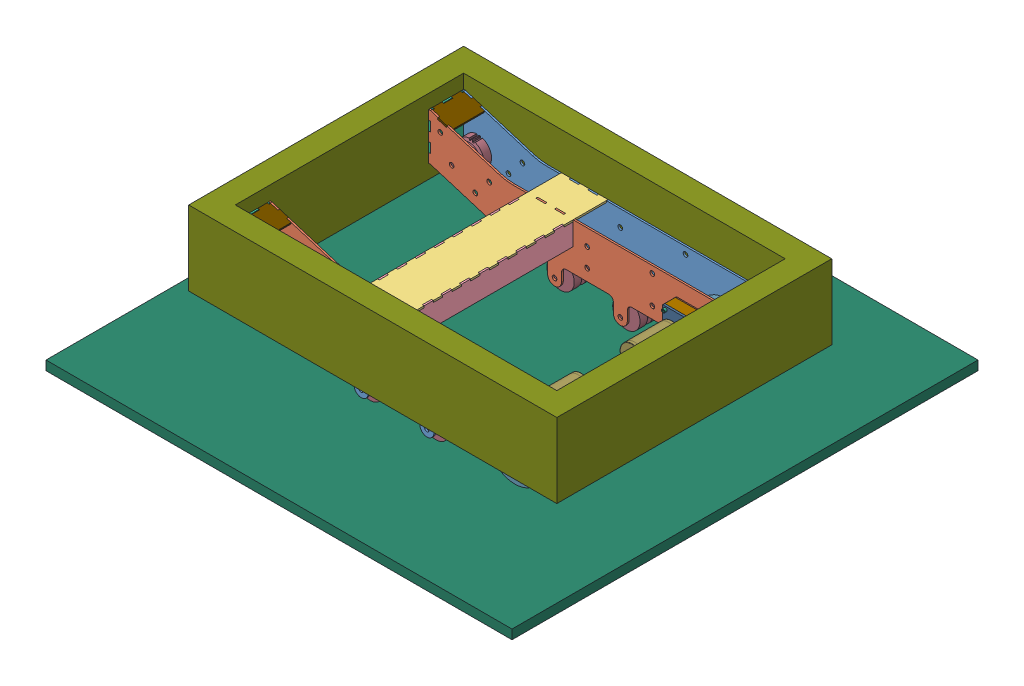
SolidWorks assembly base v2, configuration Default. Lengths in mm.
Overall size (1270 330.2 1270).
109 component instances, 36 part files, 86 mates.
Components (placement in the parent):
- outer wall-1: outer wall [Default] at origin size (876.3 248.48 4.83)
- inner wall-1: inner wall [Default] at (-656.7743 299.8998 -90.424) size (871.47 248.48 4.83)
- inner wall-2: inner wall [Default] at (-656.7743 299.8998 -527.05) size (871.47 248.48 4.83)
- outer wall-2: outer wall [Default] at (0 0 -617.474) size (876.3 248.48 4.83)
- center top support-1: center top support [Default] at (-609.6 198.374 -617.474) x (0 0 1) z (-1 0 0) size (622.3 4.83 127)
- center side support-1: center side support [Default] at (-487.426 139.7 4.826) x (0 0 -1) z (1 0 0) size (441.45 63.5 4.83)
- center side support-2: center side support [Default] at (-604.774 139.7 -617.474) x (0 0 1) z (-1 0 0) size (441.45 63.5 4.83)
- back wall-1: back wall [Default] at (-9.652 76.2 4.826) x (0 0 -1) z (1 0 0) size (441.45 127 4.83)
- front plate-1: front plate [Default] at (-871.474 139.7 -90.424) x (0 0 1) z (-1 0 0) size (95.25 127 4.83)
- front plate-2: front plate [Default] at (-871.474 139.7 -617.474) x (0 0 1) z (-1 0 0) size (95.25 127 4.83)
- back plate left-1: back plate left [Default] at (-4.826 76.2 4.826) x (0 0 -1) z (1 0 0) size (315.98 127 4.83)
- back plate right-1: back plate right [Default] at (-4.826 76.2 4.826) x (0 0 -1) z (1 0 0) size (311.15 127 4.83)
- am-0145+Updated+Toughbox+2015-1: am-0145+Updated+Toughbox+2015 [Default] at (-172.8426 75.0742 -202.6767) size (127.03 127 97.81)
  - am-2650 TB Spacer-1: am-2650 TB Spacer [Default] at (-20.7449 79.3887 80.3249) size (127 14.35 28.75)
  - am-0155 Toughbox Motor Plate-1: am-0155 Toughbox Motor Plate [Default] at (21.1445 38.6364 74.7369) x (1 0 0) z (0 1 0) size (127 5.59 127)
  - am-2650 TB Spacer-2: am-2650 TB Spacer [Default] at (90.4055 -31.7363 80.3249) x (-1 0 0) z (0 0 1) size (127 14.35 28.75)
  - Toughbox d02 am-0261-1: Toughbox d02 am-0261 [Default] at (21.1699 38.6364 109.0777) x (1 0 0) z (0 1 0) size (127 3.17 127)
  - FR6ZZ Bearing-1: FR6ZZ Bearing [Default] at (40.6889 12.4563 81.8489) x (0.923728 0.383049 0) z (0 0 -1) size (24.69 24.69 7.16)
  - FR6ZZ Bearing-2: FR6ZZ Bearing [Default] at (40.6889 53.1471 81.8489) x (0.923728 0.383049 0) z (0 0 -1) size (24.69 24.69 7.16)
  - 10-32x0500_shcs_HX-SHCS 0.19-32x1.375x1-C-1: 10-32x0500_shcs_HX-SHCS 0.19-32x1.375x1-C [Default] at (-3.3906 4.7762 85.1509) x (0 0 -1) z (1 0 0) size (17.53 7.94 7.94)
  - 10-32x0500_shcs_HX-SHCS 0.19-32x1.375x1-C-2: 10-32x0500_shcs_HX-SHCS 0.19-32x1.375x1-C [Default] at (-3.3906 55.5762 85.1509) x (0 0 -1) z (1 0 0) size (17.53 7.94 7.94)
  - 10-32x0500_shcs_HX-SHCS 0.19-32x1.375x1-C-3: 10-32x0500_shcs_HX-SHCS 0.19-32x1.375x1-C [Default] at (73.0258 55.5762 85.1509) x (0 0 -1) z (1 0 0) size (17.53 7.94 7.94)
  - 10-32x0500_shcs_HX-SHCS 0.19-32x1.375x1-C-4: 10-32x0500_shcs_HX-SHCS 0.19-32x1.375x1-C [Default] at (73.0258 4.7762 85.1509) x (0 0 -1) z (1 0 0) size (17.53 7.94 7.94)
  - 5-16 washer-1: 5-16 washer [Default] at (-3.3906 30.1762 78.8009) size (17.53 17.53 1.47)
  - 5-16 washer-2: 5-16 washer [Default] at (-3.3906 30.1762 80.2741) size (17.53 17.53 1.47)
  - 5-16 washer-3: 5-16 washer [Default] at (73.0258 30.1762 78.8009) size (17.53 17.53 1.47)
  - 5-16 washer-4: 5-16 washer [Default] at (73.0258 30.1762 80.2741) size (17.53 17.53 1.47)
  - Toughbox Small Hex Shaft-1: Toughbox Small Hex Shaft [Default] at (34.8176 44.1716 75.8037) x (0.5 -0.866025 0) z (0 0 1) size (11 9.53 38.11)
  - TB Output Shaft-1: TB Output Shaft [Default] at (-2.2613 22.7278 107.2489) x (-0.997664 0.068316 0) z (0.068316 0.997664 0) size (14.66 92.33 12.7)
  - FR6ZZ Bearing-3: FR6ZZ Bearing [Default] at (43.7045 38.1296 107.5537) size (24.69 24.69 7.16)
  - FR8ZZ Bearing-1: FR8ZZ Bearing [Default] at (43.7045 -2.5612 107.5029) size (31.75 31.75 7.95)
  - 14T CIM Gear-1: 14T CIM Gear [Default] at (-3.3906 30.1762 81.7473) size (20.03 20.32 12.7)
  - 14T CIM Gear-2: 14T CIM Gear [Default] at (73.0258 30.1762 81.7473) x (0.98536 0.170489 0) z (0 0 1) size (20.03 20.32 12.7)
  - 8mm_spring_clip am-0033-1: 8mm_spring_clip am-0033 [Default] at (-3.3906 30.1762 94.4473) x (0 0 1) z (-1 0 0) size (1.12 14.83 14.83)
  - 8mm_spring_clip am-0033-2: 8mm_spring_clip am-0033 [Default] at (73.0258 30.1762 94.4473) x (0 0 1) z (-1 0 0) size (1.12 14.83 14.83)
  - 500-e-klip_smart-1: 500-e-klip_smart [Default] at (62.138 11.0174 96.4031) x (1 0 0) z (0 1 0) size (19.07 1.27 20.95)
  - 50T 20dp 375hex_Inch - Spur gear 20DP 50T 14.5PA .372FW ---S50N3.0H2.0L0.25N-1: 50T 20dp 375hex_Inch - Spur gear 20DP 50T 14.5PA .372FW ---S50N3.0H2.0L0.25N [Default] at (34.8176 44.1716 92.0089) x (0 0 -1) z (1 0 0) size (10.16 65.97 66.04)
  - 14T 20dp 375hex_Inch - Spur gear 20DP 14T 14.5PA .568FW ---S14N3.0H2.0L0.25N-1: 14T 20dp 375hex_Inch - Spur gear 20DP 14T 14.5PA .568FW ---S14N3.0H2.0L0.25N [Default] at (34.843 44.1716 92.0089) x (0 0 1) z (-1 0 0) size (15.14 19.97 20.32)
  - 50T 20dp 500hex-1: 50T 20dp 500hex [Default] at (34.8176 3.4808 96.4031) x (0.997664 -0.068316 0) z (0 0 1) size (65.97 66.04 10.62)
  - SHCS 14-20 x 2-1: SHCS 14-20 x 2 [Default] at (90.3801 79.3887 68.1837) x (1 0 0) z (0 1 0) size (9.53 57.35 9.53)
  - SHCS 14-20 x 2-2: SHCS 14-20 x 2 [Default] at (-20.7449 79.3887 68.1837) x (1 0 0) z (0 1 0) size (9.53 57.35 9.53)
  - SHCS 14-20 x 2-3: SHCS 14-20 x 2 [Default] at (-20.7449 -31.7363 68.1837) x (1 0 0) z (0 1 0) size (9.53 57.35 9.53)
  - SHCS 14-20 x 2-4: SHCS 14-20 x 2 [Default] at (90.3801 -31.7363 68.1837) x (1 0 0) z (0 1 0) size (9.53 57.35 9.53)
  - 14-20 Nylock Nut_97135A210-1: 14-20 Nylock Nut_97135A210 [Default] at (-20.7195 79.3887 112.2527) x (1 0 0) z (0 -1 0) size (11.11 8.13 12.83)
  - 14-20 Nylock Nut_97135A210-2: 14-20 Nylock Nut_97135A210 [Default] at (-20.7195 -31.7363 112.2527) x (1 0 0) z (0 -1 0) size (11.11 8.13 12.83)
  - 14-20 Nylock Nut_97135A210-3: 14-20 Nylock Nut_97135A210 [Default] at (90.4055 -31.7363 112.2527) x (1 0 0) z (0 -1 0) size (11.11 8.13 12.83)
  - 14-20 Nylock Nut_97135A210-4: 14-20 Nylock Nut_97135A210 [Default] at (90.4055 79.3887 112.2527) x (1 0 0) z (0 -1 0) size (11.11 8.13 12.83)
  - 0.25 Flat Washer_Preferred Wide FW 0.25-1: 0.25 Flat Washer_Preferred Wide FW 0.25 [Default] at (34.8176 3.4808 154.3659) x (0 0 -1) z (1 0 0) size (1.4 15.88 15.88)
  - BHCS 14-20 x 0.5-1: BHCS 14-20 x 0.5 [Default] at (34.8176 3.4808 159.8269) x (0.554675 -0.832067 0) z (-0.832067 -0.554675 0) size (11.69 16.79 11.69)
  - 2mm x 2mm x 10mm Machine Key_smart-1: 2mm x 2mm x 10mm Machine Key_smart [Default] at (-25.2074 30.9762 84.4473) x (0 0 1) z (0 -1 0) size (10 2 2)
  - 2mm x 2mm x 10mm Machine Key_smart-2: 2mm x 2mm x 10mm Machine Key_smart [Default] at (79.0195 13.1317 84.4473) x (0 0 1) z (0.98536 0.170489 0) size (10 2 2)
  - 125 x 124 x 700 Machine Key-1: 125 x 124 x 700 Machine Key [Default] at (33.4941 11.4893 125.5831) x (0 0 1) z (-0.997664 0.068316 0) size (17.78 3.17 3.17)
- am-0145+Updated+Toughbox+2015-2: am-0145+Updated+Toughbox+2015 [Default] at (-103.2074 75.0742 -409.9713) x (-1 0 0) z (0 0 -1) size (127.03 127 97.81)
  - am-2650 TB Spacer-1: am-2650 TB Spacer [Default] at (-20.7449 79.3887 80.3249) size (127 14.35 28.75)
  - am-0155 Toughbox Motor Plate-1: am-0155 Toughbox Motor Plate [Default] at (21.1445 38.6364 74.7369) x (1 0 0) z (0 1 0) size (127 5.59 127)
  - am-2650 TB Spacer-2: am-2650 TB Spacer [Default] at (90.4055 -31.7363 80.3249) x (-1 0 0) z (0 0 1) size (127 14.35 28.75)
  - Toughbox d02 am-0261-1: Toughbox d02 am-0261 [Default] at (21.1699 38.6364 109.0777) x (1 0 0) z (0 1 0) size (127 3.17 127)
  - FR6ZZ Bearing-1: FR6ZZ Bearing [Default] at (40.6889 12.4563 81.8489) x (0.923728 0.383049 0) z (0 0 -1) size (24.69 24.69 7.16)
  - FR6ZZ Bearing-2: FR6ZZ Bearing [Default] at (40.6889 53.1471 81.8489) x (0.923728 0.383049 0) z (0 0 -1) size (24.69 24.69 7.16)
  - 10-32x0500_shcs_HX-SHCS 0.19-32x1.375x1-C-1: 10-32x0500_shcs_HX-SHCS 0.19-32x1.375x1-C [Default] at (-3.3906 4.7762 85.1509) x (0 0 -1) z (1 0 0) size (17.53 7.94 7.94)
  - 10-32x0500_shcs_HX-SHCS 0.19-32x1.375x1-C-2: 10-32x0500_shcs_HX-SHCS 0.19-32x1.375x1-C [Default] at (-3.3906 55.5762 85.1509) x (0 0 -1) z (1 0 0) size (17.53 7.94 7.94)
  - 10-32x0500_shcs_HX-SHCS 0.19-32x1.375x1-C-3: 10-32x0500_shcs_HX-SHCS 0.19-32x1.375x1-C [Default] at (73.0258 55.5762 85.1509) x (0 0 -1) z (1 0 0) size (17.53 7.94 7.94)
  - 10-32x0500_shcs_HX-SHCS 0.19-32x1.375x1-C-4: 10-32x0500_shcs_HX-SHCS 0.19-32x1.375x1-C [Default] at (73.0258 4.7762 85.1509) x (0 0 -1) z (1 0 0) size (17.53 7.94 7.94)
  - 5-16 washer-1: 5-16 washer [Default] at (-3.3906 30.1762 78.8009) size (17.53 17.53 1.47)
  - 5-16 washer-2: 5-16 washer [Default] at (-3.3906 30.1762 80.2741) size (17.53 17.53 1.47)
  - 5-16 washer-3: 5-16 washer [Default] at (73.0258 30.1762 78.8009) size (17.53 17.53 1.47)
  - 5-16 washer-4: 5-16 washer [Default] at (73.0258 30.1762 80.2741) size (17.53 17.53 1.47)
  - Toughbox Small Hex Shaft-1: Toughbox Small Hex Shaft [Default] at (34.8176 44.1716 75.8037) x (0.5 -0.866025 0) z (0 0 1) size (11 9.53 38.11)
  - TB Output Shaft-1: TB Output Shaft [Default] at (-2.2613 22.7278 107.2489) x (-0.997664 0.068316 0) z (0.068316 0.997664 0) size (14.66 92.33 12.7)
  - FR6ZZ Bearing-3: FR6ZZ Bearing [Default] at (43.7045 38.1296 107.5537) size (24.69 24.69 7.16)
  - FR8ZZ Bearing-1: FR8ZZ Bearing [Default] at (43.7045 -2.5612 107.5029) size (31.75 31.75 7.95)
  - 14T CIM Gear-1: 14T CIM Gear [Default] at (-3.3906 30.1762 81.7473) size (20.03 20.32 12.7)
  - 14T CIM Gear-2: 14T CIM Gear [Default] at (73.0258 30.1762 81.7473) x (0.98536 0.170489 0) z (0 0 1) size (20.03 20.32 12.7)
  - 8mm_spring_clip am-0033-1: 8mm_spring_clip am-0033 [Default] at (-3.3906 30.1762 94.4473) x (0 0 1) z (-1 0 0) size (1.12 14.83 14.83)
  - 8mm_spring_clip am-0033-2: 8mm_spring_clip am-0033 [Default] at (73.0258 30.1762 94.4473) x (0 0 1) z (-1 0 0) size (1.12 14.83 14.83)
  - 500-e-klip_smart-1: 500-e-klip_smart [Default] at (62.138 11.0174 96.4031) x (1 0 0) z (0 1 0) size (19.07 1.27 20.95)
  - 50T 20dp 375hex_Inch - Spur gear 20DP 50T 14.5PA .372FW ---S50N3.0H2.0L0.25N-1: 50T 20dp 375hex_Inch - Spur gear 20DP 50T 14.5PA .372FW ---S50N3.0H2.0L0.25N [Default] at (34.8176 44.1716 92.0089) x (0 0 -1) z (1 0 0) size (10.16 65.97 66.04)
  - 14T 20dp 375hex_Inch - Spur gear 20DP 14T 14.5PA .568FW ---S14N3.0H2.0L0.25N-1: 14T 20dp 375hex_Inch - Spur gear 20DP 14T 14.5PA .568FW ---S14N3.0H2.0L0.25N [Default] at (34.843 44.1716 92.0089) x (0 0 1) z (-1 0 0) size (15.14 19.97 20.32)
  - 50T 20dp 500hex-1: 50T 20dp 500hex [Default] at (34.8176 3.4808 96.4031) x (0.997664 -0.068316 0) z (0 0 1) size (65.97 66.04 10.62)
  - SHCS 14-20 x 2-1: SHCS 14-20 x 2 [Default] at (90.3801 79.3887 68.1837) x (1 0 0) z (0 1 0) size (9.53 57.35 9.53)
  - SHCS 14-20 x 2-2: SHCS 14-20 x 2 [Default] at (-20.7449 79.3887 68.1837) x (1 0 0) z (0 1 0) size (9.53 57.35 9.53)
  - SHCS 14-20 x 2-3: SHCS 14-20 x 2 [Default] at (-20.7449 -31.7363 68.1837) x (1 0 0) z (0 1 0) size (9.53 57.35 9.53)
  - SHCS 14-20 x 2-4: SHCS 14-20 x 2 [Default] at (90.3801 -31.7363 68.1837) x (1 0 0) z (0 1 0) size (9.53 57.35 9.53)
  - 14-20 Nylock Nut_97135A210-1: 14-20 Nylock Nut_97135A210 [Default] at (-20.7195 79.3887 112.2527) x (1 0 0) z (0 -1 0) size (11.11 8.13 12.83)
  - 14-20 Nylock Nut_97135A210-2: 14-20 Nylock Nut_97135A210 [Default] at (-20.7195 -31.7363 112.2527) x (1 0 0) z (0 -1 0) size (11.11 8.13 12.83)
  - 14-20 Nylock Nut_97135A210-3: 14-20 Nylock Nut_97135A210 [Default] at (90.4055 -31.7363 112.2527) x (1 0 0) z (0 -1 0) size (11.11 8.13 12.83)
  - 14-20 Nylock Nut_97135A210-4: 14-20 Nylock Nut_97135A210 [Default] at (90.4055 79.3887 112.2527) x (1 0 0) z (0 -1 0) size (11.11 8.13 12.83)
  - 0.25 Flat Washer_Preferred Wide FW 0.25-1: 0.25 Flat Washer_Preferred Wide FW 0.25 [Default] at (34.8176 3.4808 154.3659) x (0 0 -1) z (1 0 0) size (1.4 15.88 15.88)
  - BHCS 14-20 x 0.5-1: BHCS 14-20 x 0.5 [Default] at (34.8176 3.4808 159.8269) x (0.554675 -0.832067 0) z (-0.832067 -0.554675 0) size (11.69 16.79 11.69)
  - 2mm x 2mm x 10mm Machine Key_smart-1: 2mm x 2mm x 10mm Machine Key_smart [Default] at (-25.2074 30.9762 84.4473) x (0 0 1) z (0 -1 0) size (10 2 2)
  - 2mm x 2mm x 10mm Machine Key_smart-2: 2mm x 2mm x 10mm Machine Key_smart [Default] at (79.0195 13.1317 84.4473) x (0 0 1) z (0.98536 0.170489 0) size (10 2 2)
  - 125 x 124 x 700 Machine Key-1: 125 x 124 x 700 Machine Key [Default] at (33.4941 11.4893 125.5831) x (0 0 1) z (-0.997664 0.068316 0) size (17.78 3.17 3.17)
- CIM 217-2000-1: CIM 217-2000 [Default] at (-176.2332 105.2504 -484.7082) x (0 0 1) z (-1 0 0) size (150.2 64.01 64.01)
- CIM 217-2000-2: CIM 217-2000 [Default] at (-99.8168 105.2504 -484.7082) x (0 0 1) z (-1 0 0) size (150.2 64.01 64.01)
- CIM 217-2000-3: CIM 217-2000 [Default] at (-176.2332 105.2504 -127.9398) x (0 0 -1) z (1 0 0) size (150.2 64.01 64.01)
- CIM 217-2000-4: CIM 217-2000 [Default] at (-99.8168 105.2504 -127.9398) x (0 0 -1) z (1 0 0) size (150.2 64.01 64.01)
- al55tk10k13_24-0_nohub_d-12h7-1: al55tk10k13_24-0_nohub_d-12h7 [Default] at (-353.925 37.275 -46.55) size (74.55 74.36 55)
- al55tk10k13_48-0_nohub_d-16h7-1: al55tk10k13_48-0_nohub_d-16h7 [Default] at (-138.025 78.555 -46.55) size (150.95 150.86 55)
- al55tk10k13_24-0_nohub_d-12h7-2: al55tk10k13_24-0_nohub_d-12h7 [Default] at (-353.925 37.275 -566.098) size (74.55 74.36 55)
- al55tk10k13_48-0_nohub_d-16h7-2: al55tk10k13_48-0_nohub_d-16h7 [Default] at (-138.025 78.555 -566.098) size (150.95 150.86 55)
- al55tk10k13_24-0_nohub_d-12h7-3: al55tk10k13_24-0_nohub_d-12h7 [Default] at (-533.215 40.455 -46.55) size (74.55 74.36 55)
- al55tk10k13_24-0_nohub_d-12h7-4: al55tk10k13_24-0_nohub_d-12h7 [Default] at (-813.625 166.175 -46.55) size (74.55 74.36 55)
- al55tk10k13_24-0_nohub_d-12h7-5: al55tk10k13_24-0_nohub_d-12h7 [Default] at (-813.625 166.175 -566.098) size (74.55 74.36 55)
- al55tk10k13_24-0_nohub_d-12h7-6: al55tk10k13_24-0_nohub_d-12h7 [Default] at (-533.215 40.455 -566.098) size (74.55 74.36 55)
- ground-1: ground [Default] at (-1073.15 0 323.85) size (1270 25.4 1270)
- bumper zone-1: bumper zone [Default] at (0 0 4.826) size (1003.3 203.2 749.3)
- back top plate-1: back top plate [Default] at (-4.826 198.374 4.826) x (0 0 -1) z (1 0 0) size (441.45 4.83 63.5)
- front top plate-1: front top plate [Default] at (-876.3 263.137 -522.224) x (0.955668 -0.294445 0) z (0 0 1) size (63.5 4.83 95.25)
- front top plate-2: front top plate [Default] at (-876.3 263.137 4.826) x (0.955668 -0.294445 0) z (0 0 1) size (63.5 4.83 95.25)
Mates (geometry in assembly coordinates):
- Coincident6: coincident aligned: plane of outer wall-1 through (-95.4774 63.5 4.826) normal (0 0 1); plane of center top support-1 through (-609.6 203.2 4.826) normal (0 0 1)
- Coincident7: coincident anti-aligned: plane of outer wall-1 through (-482.6 0 0) normal (-1 0 0); plane of center top support-1 through (-482.6 203.2 -617.474) normal (1 0 0)
- Coincident8: coincident aligned: plane of outer wall-1 through (-665.3748 203.2 4.826) normal (0 1 0); plane of center top support-1 through (-609.6 203.2 -617.474) normal (0 1 0)
- Coincident10: coincident aligned: plane of inner wall-1 through (0 203.2 -85.598) normal (0 1 0); plane of center top support-1 through (-609.6 203.2 -617.474) normal (0 1 0)
- Coincident11: coincident anti-aligned: plane of inner wall-1 through (-646.2537 203.2 -90.424) normal (0 0 -1); plane of center top support-1 through (-609.6 203.2 -90.424) normal (0 0 1)
- Coincident12: coincident anti-aligned: plane of inner wall-1 through (-482.6 203.2 -85.598) normal (-1 0 0); plane of center top support-1 through (-482.6 203.2 -617.474) normal (1 0 0)
- Coincident13: coincident anti-aligned: plane of inner wall-2 through (-482.6 203.2 -522.224) normal (-1 0 0); plane of center top support-1 through (-482.6 203.2 -617.474) normal (1 0 0)
- Coincident14: coincident aligned: plane of inner wall-2 through (0 203.2 -522.224) normal (0 1 0); plane of center top support-1 through (-609.6 203.2 -617.474) normal (0 1 0)
- Coincident15: coincident anti-aligned: plane of inner wall-2 through (-646.2537 203.2 -522.224) normal (0 0 1); plane of center top support-1 through (-609.6 203.2 -522.224) normal (0 0 -1)
- Coincident16: coincident aligned: plane of outer wall-2 through (-95.4774 63.5 -617.474) normal (0 0 -1); plane of center top support-1 through (-609.6 203.2 -617.474) normal (0 0 -1)
- Coincident17: coincident aligned: plane of outer wall-2 through (-665.3748 203.2 -612.648) normal (0 1 0); plane of center top support-1 through (-609.6 203.2 -617.474) normal (0 1 0)
- Coincident18: coincident anti-aligned: plane of outer wall-2 through (-609.6 0 -617.474) normal (1 0 0); plane of center top support-1 through (-609.6 203.2 -617.474) normal (-1 0 0)
- Coincident19: coincident aligned: plane of center top support-1 through (-482.6 203.2 -617.474) normal (1 0 0); plane of center side support-1 through (-482.6 139.7 4.826) normal (1 0 0)
- Coincident20: coincident aligned: plane of center top support-1 through (-609.6 203.2 -617.474) normal (0 1 0); plane of center side support-1 through (-482.6 203.2 -115.824) normal (0 1 0)
- Coincident21: coincident aligned: plane of inner wall-1 through (-646.2537 203.2 -85.598) normal (0 0 1); plane of center side support-1 through (-482.6 177.8 -85.598) normal (0 0 1)
- Coincident22: coincident aligned: plane of center top support-1 through (-609.6 203.2 -617.474) normal (-1 0 0); plane of center side support-2 through (-609.6 139.7 -617.474) normal (-1 0 0)
- Coincident23: coincident aligned: plane of center top support-1 through (-609.6 203.2 -617.474) normal (0 1 0); plane of center side support-2 through (-609.6 203.2 -496.824) normal (0 1 0)
- Coincident24: coincident aligned: plane of inner wall-1 through (-646.2537 203.2 -85.598) normal (0 0 1); plane of center side support-2 through (-609.6 177.8 -85.598) normal (0 0 1)
- Coincident25: coincident aligned: plane of inner wall-1 through (-4.826 152.4 -85.598) normal (1 0 0); plane of back wall-1 through (-4.826 76.2 4.826) normal (1 0 0)
- Coincident26: coincident aligned: plane of inner wall-1 through (-646.2537 203.2 -85.598) normal (0 0 1); plane of back wall-1 through (-4.826 152.4 -85.598) normal (0 0 1)
- Coincident27: coincident aligned: plane of inner wall-1 through (0 203.2 -85.598) normal (0 1 0); plane of back wall-1 through (-4.826 203.2 -85.598) normal (0 1 0)
- Coincident28: coincident aligned: plane of inner wall-1 through (-876.3 266.7 -85.598) normal (-1 0 0); plane of front plate-1 through (-876.3 139.7 -90.424) normal (-1 0 0)
- Coincident29: coincident aligned: plane of outer wall-1 through (-95.4774 63.5 4.826) normal (0 0 1); plane of front plate-1 through (-876.3 215.9 4.826) normal (0 0 1)
- Coincident30: coincident aligned: plane of outer wall-1 through (-876.3 266.7 4.826) normal (0 1 0); plane of front plate-1 through (-876.3 266.7 -85.598) normal (0 1 0)
- Coincident31: coincident aligned: plane of outer wall-2 through (-876.3 139.7 -612.648) normal (-1 0 0); plane of front plate-2 through (-876.3 139.7 -617.474) normal (-1 0 0)
- Coincident32: coincident aligned: plane of inner wall-2 through (-646.2537 203.2 -522.224) normal (0 0 1); plane of front plate-2 through (-876.3 215.9 -522.224) normal (0 0 1)
- Coincident33: coincident aligned: plane of inner wall-2 through (-871.474 266.7 -522.224) normal (0 1 0); plane of front plate-2 through (-876.3 266.7 -612.648) normal (0 1 0)
- Coincident34: coincident aligned: plane of outer wall-1 through (0 152.4 4.826) normal (1 0 0); plane of back plate left-1 through (0 76.2 4.826) normal (1 0 0)
- Coincident35: coincident aligned: plane of outer wall-1 through (-95.4774 63.5 4.826) normal (0 0 1); plane of back plate left-1 through (0 127 4.826) normal (0 0 1)
- Coincident36: coincident aligned: plane of outer wall-1 through (-665.3748 203.2 4.826) normal (0 1 0); plane of back plate left-1 through (0 203.2 0) normal (0 1 0)
- Coincident37: coincident aligned: plane of back plate left-1 through (0 76.2 4.826) normal (1 0 0); plane of back plate right-1 through (0 76.2 4.826) normal (1 0 0)
- Coincident38: coincident aligned: plane of back plate left-1 through (0 203.2 0) normal (0 1 0); plane of back plate right-1 through (0 203.2 -306.324) normal (0 1 0)
- Coincident39: coincident anti-aligned: plane of back plate left-1 through (0 203.2 -306.324) normal (0 0 -1); plane of back plate right-1 through (0 203.2 -306.324) normal (0 0 1)
- Concentric1: concentric aligned: cylinder of inner wall-1 through (-138.025 78.555 -85.598) axis (0 0 -1) radius 6.35; cylinder of am-0145+Updated+Toughbox+2015-1/TB Output Shaft-1 through (-138.025 78.555 -48.3108) axis (0 0 -1) radius 6.3373
- Coincident40: coincident anti-aligned: plane of inner wall-1 through (-646.2537 203.2 -90.424) normal (0 0 -1); plane of am-0145+Updated+Toughbox+2015-1/Toughbox d02 am-0261-1 through (-75.2934 36.1941 -90.424) normal (0 0 1)
- Coincident41: coincident anti-aligned: plane of inner wall-2 through (-646.2537 203.2 -522.224) normal (0 0 1); plane of am-0145+Updated+Toughbox+2015-2/Toughbox d02 am-0261-1 through (-200.7567 36.1941 -522.224) normal (0 0 -1)
- Parallel1: parallel aligned: plane of inner wall-2 through (0 203.2 -522.224) normal (0 1 0); plane of am-0145+Updated+Toughbox+2015-2/am-2650 TB Spacer-1 through (-75.2997 162.3877 -519.049) normal (0 1 0)
- Concentric2: concentric anti-aligned: cylinder of inner wall-2 through (-138.025 78.555 -522.224) axis (0 0 -1) radius 6.35; cylinder of am-0145+Updated+Toughbox+2015-2/TB Output Shaft-1 through (-138.025 78.555 -564.3372) axis (0 0 1) radius 6.3373
- Parallel2: parallel aligned: plane of am-0145+Updated+Toughbox+2015-1/am-2650 TB Spacer-1 through (-200.7503 162.3877 -93.599) normal (0 1 0); plane of inner wall-1 through (0 203.2 -85.598) normal (0 1 0)
- Concentric3: concentric anti-aligned: cylinder of am-0145+Updated+Toughbox+2015-2/am-0155 Toughbox Motor Plate-1 through (-176.2332 105.2504 -484.7082) axis (0 0 -1) radius 10.414; cylinder of CIM 217-2000-1 through (-176.2332 105.2504 -484.7082) axis (0 0 1) radius 4
- Concentric4: concentric aligned: cylinder of am-0145+Updated+Toughbox+2015-2/10-32x0500_shcs_HX-SHCS 0.19-32x1.375x1-C-3 through (-176.2332 130.6504 -526.8722) axis (0 0 -1) radius 2.413; cylinder of CIM 217-2000-1 through (-176.2332 130.6504 -484.7082) axis (0 0 -1) radius 2.0193
- Coincident44: coincident anti-aligned: plane of am-0145+Updated+Toughbox+2015-2/am-0155 Toughbox Motor Plate-1 through (-200.7313 36.1941 -484.7082) normal (0 0 1); plane of CIM 217-2000-1 through (-176.2332 114.7754 -484.7082) normal (0 0 -1)
- Concentric5: concentric anti-aligned: cylinder of am-0145+Updated+Toughbox+2015-2/am-0155 Toughbox Motor Plate-1 through (-99.8168 105.2504 -484.7082) axis (0 0 -1) radius 10.414; cylinder of CIM 217-2000-2 through (-99.8168 105.2504 -484.7082) axis (0 0 1) radius 4
- Concentric6: concentric aligned: cylinder of am-0145+Updated+Toughbox+2015-2/10-32x0500_shcs_HX-SHCS 0.19-32x1.375x1-C-2 through (-99.8168 130.6504 -526.8722) axis (0 0 -1) radius 2.413; cylinder of CIM 217-2000-2 through (-99.8168 130.6504 -484.7082) axis (0 0 -1) radius 2.0193
- Coincident45: coincident anti-aligned: plane of am-0145+Updated+Toughbox+2015-2/am-0155 Toughbox Motor Plate-1 through (-200.7313 36.1941 -484.7082) normal (0 0 1); plane of CIM 217-2000-2 through (-99.8168 114.7754 -484.7082) normal (0 0 -1)
- Concentric7: concentric anti-aligned: cylinder of am-0145+Updated+Toughbox+2015-1/am-0155 Toughbox Motor Plate-1 through (-176.2332 105.2504 -127.9398) axis (0 0 1) radius 10.414; cylinder of CIM 217-2000-3 through (-176.2332 105.2504 -127.9398) axis (0 0 -1) radius 4
- Concentric8: concentric aligned: cylinder of am-0145+Updated+Toughbox+2015-1/10-32x0500_shcs_HX-SHCS 0.19-32x1.375x1-C-2 through (-176.2332 130.6504 -85.7758) axis (0 0 1) radius 2.413; cylinder of CIM 217-2000-3 through (-176.2332 130.6504 -127.9398) axis (0 0 1) radius 2.0193
- Coincident46: coincident anti-aligned: plane of am-0145+Updated+Toughbox+2015-1/am-0155 Toughbox Motor Plate-1 through (-75.3188 36.1941 -127.9398) normal (0 0 -1); plane of CIM 217-2000-3 through (-176.2332 114.7754 -127.9398) normal (0 0 1)
- Concentric9: concentric anti-aligned: cylinder of am-0145+Updated+Toughbox+2015-1/am-0155 Toughbox Motor Plate-1 through (-99.8168 105.2504 -127.9398) axis (0 0 1) radius 10.414; cylinder of CIM 217-2000-4 through (-99.8168 105.2504 -127.9398) axis (0 0 -1) radius 4
- Concentric10: concentric aligned: cylinder of am-0145+Updated+Toughbox+2015-1/10-32x0500_shcs_HX-SHCS 0.19-32x1.375x1-C-3 through (-99.8168 130.6504 -85.7758) axis (0 0 1) radius 2.413; cylinder of CIM 217-2000-4 through (-99.8168 130.6504 -127.9398) axis (0 0 1) radius 2.0193
- Coincident47: coincident anti-aligned: plane of am-0145+Updated+Toughbox+2015-1/am-0155 Toughbox Motor Plate-1 through (-75.3188 36.1941 -127.9398) normal (0 0 -1); plane of CIM 217-2000-4 through (-99.8168 114.7754 -127.9398) normal (0 0 1)
- Coincident48: coincident aligned: plane of al55tk10k13_48-0_nohub_d-16h7-1 through (-138.025 78.555 -19.05) normal (0 0 1); plane of al55tk10k13_24-0_nohub_d-12h7-4 through (-813.625 166.175 -19.05) normal (0 0 1)
- Coincident49: coincident aligned: plane of al55tk10k13_48-0_nohub_d-16h7-1 through (-138.025 78.555 -19.05) normal (0 0 1); plane of al55tk10k13_24-0_nohub_d-12h7-3 through (-533.215 40.455 -19.05) normal (0 0 1)
- Coincident50: coincident aligned: plane of al55tk10k13_24-0_nohub_d-12h7-1 through (-353.925 37.275 -19.05) normal (0 0 1); plane of al55tk10k13_48-0_nohub_d-16h7-1 through (-138.025 78.555 -19.05) normal (0 0 1)
- Concentric12: concentric anti-aligned: cylinder of outer wall-1 through (-138.025 78.555 4.826) axis (0 0 -1) radius 6.35; cylinder of al55tk10k13_48-0_nohub_d-16h7-1 through (-138.025 78.555 -13.55) axis (0 0 1) radius 8
- Concentric13: concentric anti-aligned: cylinder of outer wall-1 through (-353.925 37.275 4.826) axis (0 0 -1) radius 6.35; cylinder of al55tk10k13_24-0_nohub_d-12h7-1 through (-353.925 37.275 -13.55) axis (0 0 1) radius 6
- Concentric14: concentric anti-aligned: cylinder of outer wall-1 through (-533.215 40.455 4.826) axis (0 0 -1) radius 6.35; cylinder of al55tk10k13_24-0_nohub_d-12h7-3 through (-533.215 40.455 -13.55) axis (0 0 1) radius 6
- Concentric15: concentric anti-aligned: cylinder of outer wall-1 through (-813.625 166.175 4.826) axis (0 0 -1) radius 6.35; cylinder of al55tk10k13_24-0_nohub_d-12h7-4 through (-813.625 166.175 -13.55) axis (0 0 1) radius 6
- Distance1: distance = 19.05 mm anti-aligned: plane of al55tk10k13_48-0_nohub_d-16h7-1 through (-138.025 78.555 -19.05) normal (0 0 1); plane of outer wall-1 through (-95.4774 63.5 0) normal (0 0 -1)
- Coincident52: coincident aligned: plane of al55tk10k13_24-0_nohub_d-12h7-2 through (-353.925 37.275 -593.598) normal (0 0 -1); plane of al55tk10k13_48-0_nohub_d-16h7-2 through (-138.025 78.555 -593.598) normal (0 0 -1)
- Coincident53: coincident aligned: plane of al55tk10k13_48-0_nohub_d-16h7-2 through (-138.025 78.555 -593.598) normal (0 0 -1); plane of al55tk10k13_24-0_nohub_d-12h7-6 through (-533.215 40.455 -593.598) normal (0 0 -1)
- Coincident54: coincident aligned: plane of al55tk10k13_48-0_nohub_d-16h7-2 through (-138.025 78.555 -593.598) normal (0 0 -1); plane of al55tk10k13_24-0_nohub_d-12h7-5 through (-813.625 166.175 -593.598) normal (0 0 -1)
- Concentric16: concentric anti-aligned: cylinder of outer wall-2 through (-813.625 166.175 -612.648) axis (0 0 -1) radius 6.35; cylinder of al55tk10k13_24-0_nohub_d-12h7-5 through (-813.625 166.175 -533.098) axis (0 0 1) radius 6
- Concentric17: concentric anti-aligned: cylinder of outer wall-2 through (-533.215 40.455 -612.648) axis (0 0 -1) radius 6.35; cylinder of al55tk10k13_24-0_nohub_d-12h7-6 through (-533.215 40.455 -533.098) axis (0 0 1) radius 6
- Concentric18: concentric anti-aligned: cylinder of outer wall-2 through (-353.925 37.275 -612.648) axis (0 0 -1) radius 6.35; cylinder of al55tk10k13_24-0_nohub_d-12h7-2 through (-353.925 37.275 -533.098) axis (0 0 1) radius 6
- Concentric19: concentric anti-aligned: cylinder of outer wall-2 through (-138.025 78.555 -612.648) axis (0 0 -1) radius 6.35; cylinder of al55tk10k13_48-0_nohub_d-16h7-2 through (-138.025 78.555 -533.098) axis (0 0 1) radius 8
- Distance2: distance = 19.05 mm anti-aligned: plane of al55tk10k13_48-0_nohub_d-16h7-2 through (-138.025 78.555 -593.598) normal (0 0 -1); plane of outer wall-2 through (-95.4774 63.5 -612.648) normal (0 0 1)
- Coincident56: coincident aligned: plane of ground-1 through (-1073.15 0 323.85) normal (0 1 0); plane of assembly through (0 0 0) normal (0 1 0)
- Coincident60: coincident aligned: plane of outer wall-1 through (0 0 0) normal (0 0 1); plane of assembly through (0 0 0) normal (0 0 1)
- Coincident61: coincident aligned: plane of outer wall-1 through (0 0 0) normal (1 0 0); plane of assembly through (0 0 0) normal (1 0 0)
- Coincident62: coincident aligned: plane of ground-1 through (-1073.15 0 323.85) normal (0 1 0); plane of assembly through (0 0 0) normal (0 1 0)
- Distance5: distance = 323.85 mm aligned: plane of ground-1 through (-1073.15 0 323.85) normal (0 0 1); plane of assembly through (0 0 0) normal (0 0 1)
- Distance6: distance = 196.85 mm aligned: plane of ground-1 through (196.85 -25.4 323.85) normal (1 0 0); plane of assembly through (0 0 0) normal (1 0 0)
- Coincident66: coincident aligned: plane of outer wall-1 through (0 0 0) normal (0 1 0); plane of assembly through (0 0 0) normal (0 1 0)
- Coincident67: coincident anti-aligned: plane of outer wall-2 through (-95.4774 63.5 -617.474) normal (0 0 -1); plane of bumper zone-1 through (0 304.8 -617.474) normal (0 0 1)
- Coincident68: coincident anti-aligned: plane of front plate-2 through (-876.3 139.7 -617.474) normal (-1 0 0); plane of bumper zone-1 through (-876.3 304.8 4.826) normal (1 0 0)
- Coincident69: coincident aligned: plane of bumper zone-1 through (0 0 4.826) normal (0 1 0); plane of assembly through (0 0 0) normal (0 1 0)
- Coincident70: coincident aligned: plane of inner wall-1 through (-646.2537 203.2 -85.598) normal (0 0 1); plane of back top plate-1 through (-4.826 203.2 -85.598) normal (0 0 1)
- Coincident71: coincident aligned: plane of inner wall-1 through (0 203.2 -85.598) normal (0 1 0); plane of back top plate-1 through (-4.826 203.2 4.826) normal (0 1 0)
- Coincident72: coincident anti-aligned: plane of back wall-1 through (-9.652 76.2 4.826) normal (-1 0 0); plane of back top plate-1 through (-9.652 203.2 4.826) normal (1 0 0)
- Coincident73: coincident aligned: plane of inner wall-2 through (-683.6482 208.8301 -522.224) normal (0.294445 0.955668 0); plane of front top plate-1 through (-874.879 267.7491 -522.224) normal (0.294445 0.955668 0)
- Coincident74: coincident aligned: plane of inner wall-2 through (-646.2537 203.2 -522.224) normal (0 0 1); plane of front top plate-1 through (-826.3311 252.7913 -522.224) normal (0 0 1)
- Coincident75: coincident anti-aligned: plane of inner wall-2 through (-826.3311 252.7913 -522.224) normal (-0.955668 0.294445 0); plane of front top plate-1 through (-826.3311 252.7913 -527.05) normal (0.955668 -0.294445 0)
- Coincident76: coincident aligned: plane of inner wall-1 through (-683.6482 208.8301 -85.598) normal (0.294445 0.955668 0); plane of front top plate-2 through (-874.879 267.7491 4.826) normal (0.294445 0.955668 0)
- Coincident77: coincident aligned: plane of inner wall-1 through (-646.2537 203.2 -90.424) normal (0 0 -1); plane of front top plate-2 through (-850.605 260.2702 -90.424) normal (0 0 -1)
- Coincident78: coincident anti-aligned: plane of inner wall-1 through (-826.3311 252.7913 -85.598) normal (-0.955668 0.294445 0); plane of front top plate-2 through (-826.3311 252.7913 -85.598) normal (0.955668 -0.294445 0)
